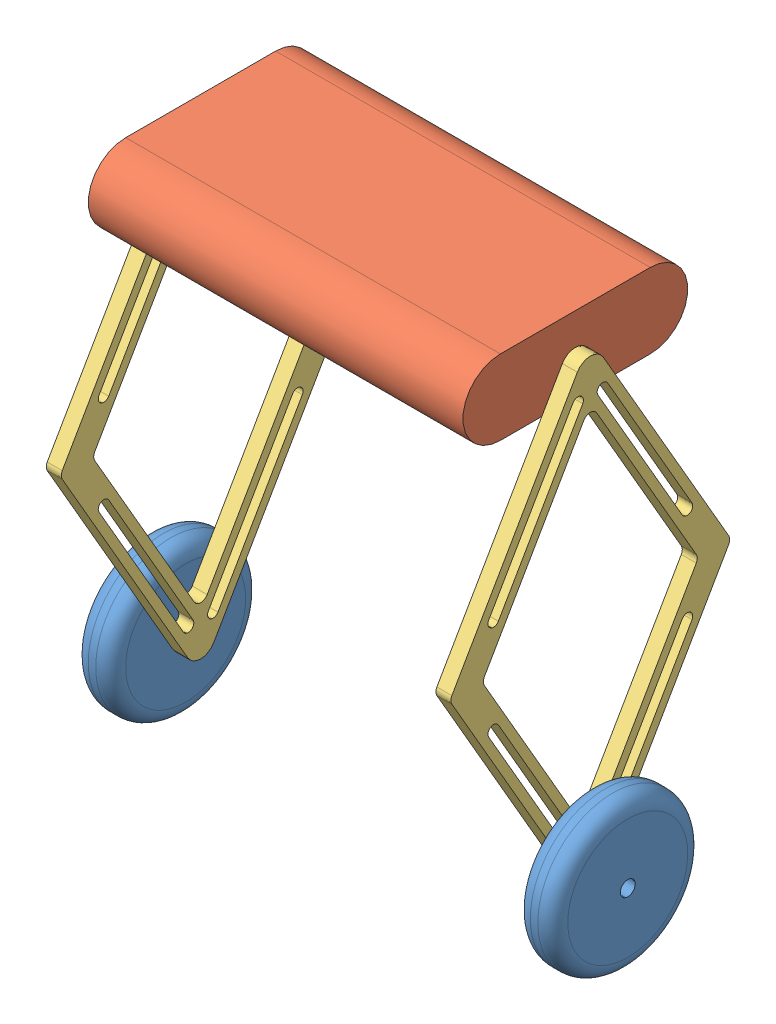
SolidWorks assembly wheel_leg, configuration 默认. Lengths in mm.
Overall size (398 807.71 543.72).
5 component instances, 3 part files, 12 mates.
Components (placement in the parent):
- 底轮-1: 底轮 [默认] at (118 -253 0) x (0 -0.963391 -0.268101) z (0 0.268101 -0.963391) size (80 20 80)
- 身体-1: 身体 [默认] at (0 -40 0) x (1 0 0) z (0 1 0) size (200 120 40)
- 腿-2: 腿 [默认] at (-100 -139 0) x (0 0 1) z (0 -1 0) size (148.87 18 244)
- 底轮-2: 底轮 [默认] at (-118 -253 0) x (0 0.839399 0.543516) z (0 -0.543516 0.839399) size (80 20 80)
- 腿-4: 腿 [默认] at (100 -139 0) x (0 0 -1) z (0 -1 0) size (148.87 18 244)
Mates (geometry in assembly coordinates):
- 同心1: concentric: cylinder of assembly; cylinder of assembly; cylinder of 底轮-1 through (128 -253 0) axis (-1 0 0) radius 4; cylinder of 底轮-2 through (-108 -253 0) axis (-1 0 0) radius 4
- 同心2: concentric: cylinder of assembly; cylinder of assembly; cylinder of 腿-2 through (-113 -253 0) axis (1 0 0) radius 4; cylinder of 底轮-2 through (-108 -253 0) axis (-1 0 0) radius 4
- 重合1: coincident: plane of assembly; plane of assembly; plane of 腿-2; plane of 底轮-2
- 同心3: concentric: cylinder of assembly; cylinder of assembly; cylinder of 底轮-1 through (128 -253 0) axis (-1 0 0) radius 4; cylinder of 腿-4 through (113 -253 0) axis (-1 0 0) radius 4
- 重合2: coincident: plane of assembly; plane of assembly; plane of 底轮-1 through (108 -253 0) normal (-1 0 0); plane of 腿-4 through (108 -139 0) normal (1 0 0)
- 重合3: coincident: plane of assembly; plane of assembly; plane of 身体-1; plane of 腿-2
- 同心4: concentric: cylinder of assembly; cylinder of assembly; cylinder of 身体-1 through (-95 -25 0) axis (-1 0 0) radius 4; cylinder of 腿-2 through (-95 -25 0) axis (-1 0 0) radius 4
- 同心5: concentric: cylinder of assembly; cylinder of assembly; cylinder of 身体-1 through (95 -25 0) axis (1 0 0) radius 4; cylinder of 腿-4 through (95 -25 0) axis (1 0 0) radius 4
- 重合6: coincident: plane of assembly; plane of assembly; plane of 身体-1; plane of 腿-4
- 重合7: coincident: plane of assembly through (0 0 0) normal (0 1 0); plane of 身体-1; plane of assembly
- 对称1: symmetric: plane of assembly; plane of assembly; plane of 底轮-1; plane of 底轮-2; plane of assembly
- 对称2: symmetric: plane of assembly; plane of assembly; plane of 腿-2; plane of 腿-2; plane of assembly
